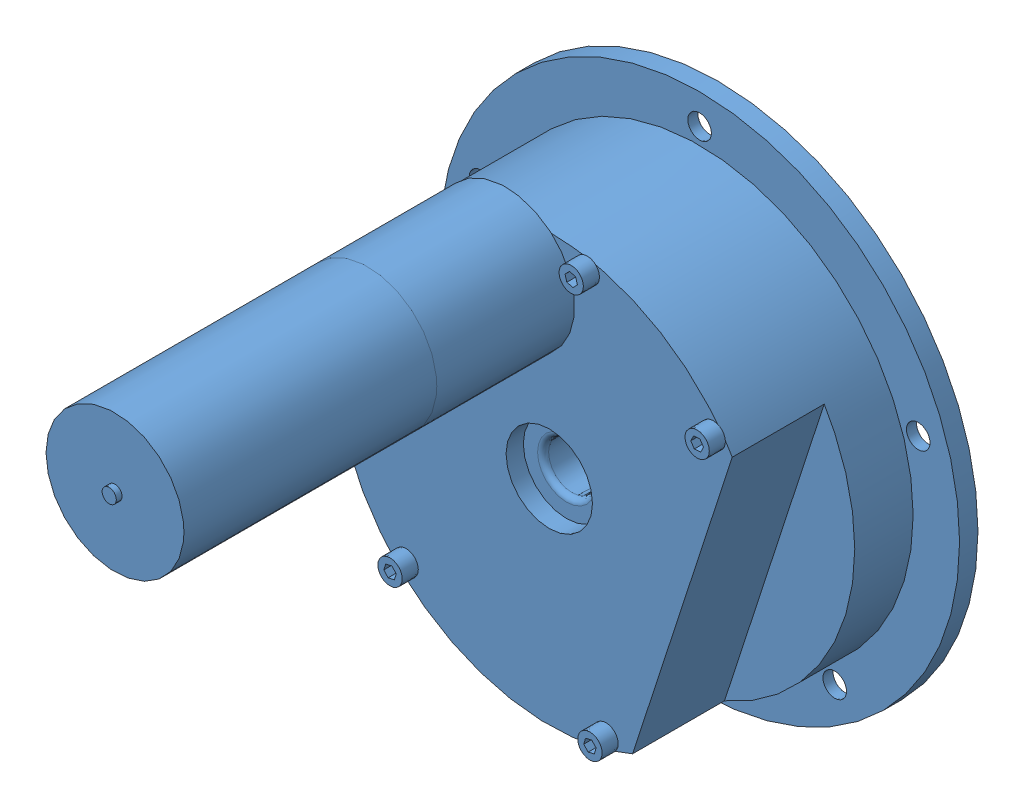
SolidWorks assembly 4.5 RPM Globe Gear Motor Assembly, configuration Default. Lengths in mm.
Overall size (143.64 143.64 156.93).
2 component instances, 2 part files, 2 mates.
Components (placement in the parent):
- 4.5 RPM Globe Gear Motor-1: 4.5 RPM Globe Gear Motor [Default] at (12.2608 12.9598 -92.9541) size (143.64 143.64 156.15)
- 4.5 RPM Globe Gear Motor Face Hub-1: 4.5 RPM Globe Gear Motor Face Hub [Default] at (12.2608 12.9598 -93.7415) x (0.891392 0.453233 0) z (-0.453233 0.891392 0) size (86.36 11.68 86.36)
Mates (geometry in assembly coordinates):
- Concentric1: concentric aligned: circle of 4.5 RPM Globe Gear Motor-1; circle of 4.5 RPM Globe Gear Motor Face Hub-1
- Distance1: distance = 3.429 mm aligned: plane of 4.5 RPM Globe Gear Motor Face Hub-1 through (12.2608 12.9598 -93.7415) normal (0 0 -1); plane of 4.5 RPM Globe Gear Motor-1 through (12.2608 12.9598 -90.3125) normal (0 0 -1)
